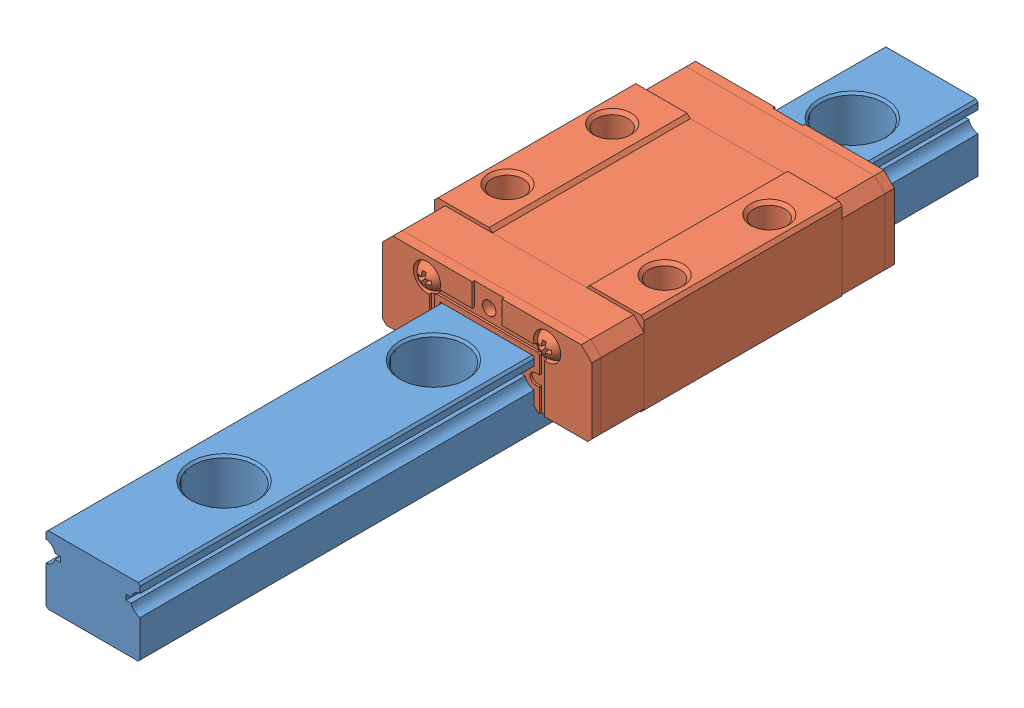
SolidWorks assembly MGN9C, configuration Default. Lengths in mm.
Overall size (20 10 80).
2 component instances, 2 part files, 3 mates.
Components (placement in the parent):
- MGNR9-1: MGNR9 [80 mm] at origin size (9 6.5 80)
- MGN9C-1: MGN9C [По умолчанию] at (0 2.75 27.9295) size (20 8 29.67)
Mates (geometry in assembly coordinates):
- 重合/共線/共點2: coordinate: point of MGNR9-1
- 同軸心1: concentric anti-aligned: cylinder of MGNR9-1 through (4.6 1.45 80) axis (0 0 -1) radius 1; cylinder of MGN9C-1 through (4.6 1.45 13.4795) axis (0 0 1) radius 1
- 同軸心2: concentric anti-aligned: cylinder of MGNR9-1 through (-4.6 1.45 80) axis (0 0 -1) radius 1; cylinder of MGN9C-1 through (-4.6 1.45 13.4795) axis (0 0 1) radius 1
